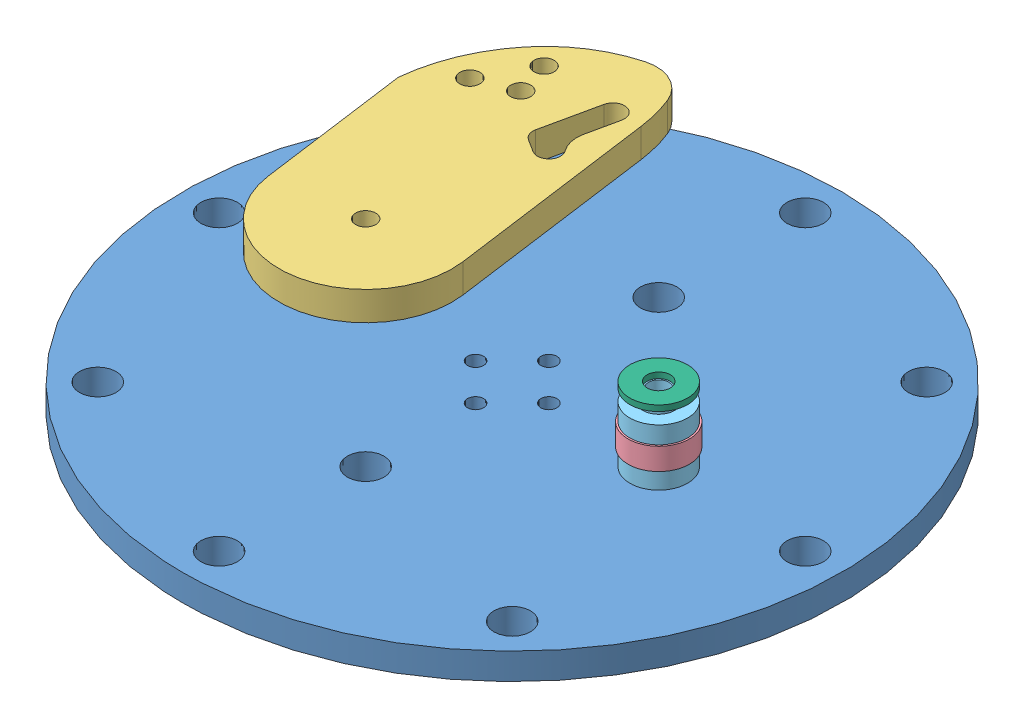
SolidWorks assembly aseembly, configuration Default. Lengths in mm.
Overall size (118.27 18.87 114.3).
9 component instances, 6 part files, 16 mates.
Components (placement in the parent):
- Default Flywheel-1: Default Flywheel [Default] at origin size (118.27 7.57 114.3)
- spacer bushing-1: spacer bushing [Default] at (-46.6641 4.572 -13.8924) x (-0.837169 0 -0.546944) z (-0.546944 0 0.837169) size (10 3.5 10)
- flag3-2: flag3 [Default] at (-25.4 11.372 0) x (0.990807 0 -0.135285) z (0.135285 0 0.990807) size (30 5 62.35)
- spacer-1: spacer [Default] at (-25.4 7.572 0) x (-0.999996 0 0.002653) z (-0.002653 0 -0.999996) size (10.6 3.8 10.6)
- spacer bushing short-1: spacer bushing short [Default] at (36.7245 0 22.7358) x (0.445847 0 0.895109) z (-0.895109 0 0.445847) size (10 5 10)
- spacer-2: spacer [Default] at (25.4 7.572 0) x (-0.949613 0 0.313424) z (-0.313424 0 -0.949613) size (10.6 3.8 10.6)
- spacer bushing-4: spacer bushing [Default] at (4.1359 4.572 -13.8924) x (-0.837169 0 -0.546944) z (-0.546944 0 0.837169) size (10 3.5 10)
- spacer bushing short-2: spacer bushing short [Default] at (3.4843 18.944 12.8398) x (-0.862824 0 0.505504) z (0.505504 0 0.862824) size (10 5 10)
- washer-1: washer [Default] at (25.4 16.372 0) size (10 1 10)
Mates (geometry in assembly coordinates):
- Concentric1: concentric aligned: cylinder of Default Flywheel-1 through (-25.4 4.572 0) axis (0 -1 0) radius 3.175; cylinder of spacer bushing-1 through (-25.4 2 0) axis (0 -1 0) radius 2.75
- Coincident1: coincident anti-aligned: plane of Default Flywheel-1 through (0 0 0) normal (0 -1 0); plane of spacer bushing-1 through (-25.4 0 0) normal (0 1 0)
- Concentric2: concentric anti-aligned: cylinder of Default Flywheel-1 through (-25.4 2.572 0) axis (0 1 0) radius 1.75; cylinder of spacer-1 through (-25.4 11.372 0) axis (0 -1 0) radius 3
- Coincident2: coincident anti-aligned: plane of Default Flywheel-1 through (-25.4 7.572 0) normal (0 1 0); plane of spacer-1 through (-25.4 7.572 0) normal (0 -1 0)
- Coincident3: coincident anti-aligned: plane of flag3-2 through (-25.4 11.372 0) normal (0 -1 0); plane of spacer-1 through (-25.4 11.372 0) normal (0 1 0)
- Concentric3: concentric aligned: cylinder of flag3-2 through (-25.4 16.372 0) axis (0 -1 0) radius 1.75; cylinder of spacer-1 through (-25.4 11.372 0) axis (0 -1 0) radius 3
- Concentric4: concentric: cylinder of Default Flywheel-1 through (25.4 4.572 0) axis (0 -1 0) radius 3.175; cylinder of spacer bushing-4 through (25.4 2 0) axis (0 -1 0) radius 2.75
- Coincident5: coincident anti-aligned: plane of Default Flywheel-1 through (0 0 0) normal (0 -1 0); plane of spacer bushing-4 through (25.4 0 0) normal (0 1 0)
- Concentric5: concentric anti-aligned: cylinder of Default Flywheel-1 through (25.4 4.572 0) axis (0 -1 0) radius 3.175; cylinder of spacer bushing short-1 through (25.4 2.572 0) axis (0 1 0) radius 1.75
- Coincident6: coincident anti-aligned: plane of Default Flywheel-1 through (0 4.572 0) normal (0 1 0); plane of spacer bushing short-1 through (25.4 4.572 0) normal (0 -1 0)
- Concentric6: concentric anti-aligned: cylinder of spacer bushing short-1 through (25.4 2.572 0) axis (0 1 0) radius 1.75; cylinder of spacer-2 through (25.4 11.372 0) axis (0 -1 0) radius 3
- Coincident7: coincident anti-aligned: plane of spacer bushing short-1 through (25.4 7.572 0) normal (0 1 0); plane of spacer-2 through (25.4 7.572 0) normal (0 -1 0)
- Concentric7: concentric anti-aligned: circle of spacer bushing short-1; cylinder of spacer bushing short-2 through (25.4 16.372 0) axis (0 -1 0) radius 1.75
- Coincident8: coincident anti-aligned: plane of spacer-2 through (25.4 11.372 0) normal (0 1 0); plane of spacer bushing short-2 through (25.4 11.372 0) normal (0 -1 0)
- Coincident9: coincident anti-aligned: plane of spacer bushing short-2 through (25.4 16.372 0) normal (0 1 0); plane of washer-1 through (4.159 16.372 -62.8522) normal (0 -1 0)
- Concentric8: concentric aligned: cylinder of spacer bushing short-2 through (25.4 16.372 0) axis (0 -1 0) radius 1.75; cylinder of washer-1 through (4.159 17.372 -62.8522) axis (0 -1 0) radius 2
